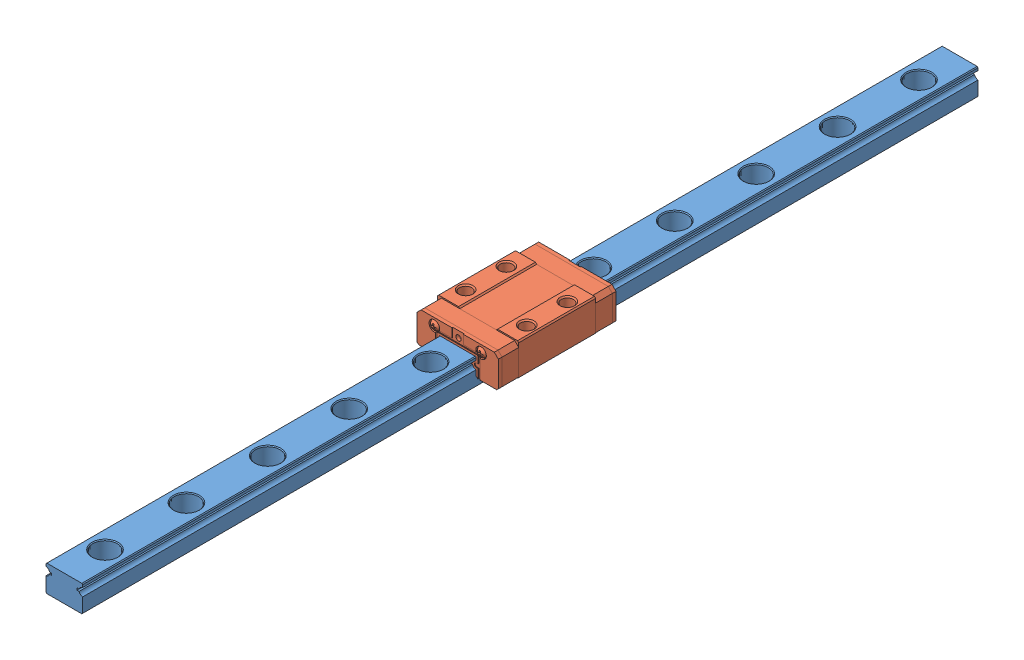
SolidWorks assembly MGN9C-250, configuration По умолчанию. Lengths in mm.
Overall size (20 10 220).
2 component instances, 2 part files, 3 mates.
Components (placement in the parent):
- MGNR9-1: MGNR9 [По умолчанию] at origin size (9 6.5 220)
- MGN9C-1: MGN9C [По умолчанию] at (0 2.75 108.8941) size (20 8 29.67)
Mates (geometry in assembly coordinates):
- 重合/共線/共點1: coordinate: point of MGNR9-1
- 同軸心1: concentric anti-aligned: cylinder of MGNR9-1 through (-4.6 1.45 220) axis (0 0 -1) radius 1; cylinder of MGN9C-1 through (-4.6 1.45 94.4441) axis (0 0 1) radius 1
- 同軸心2: concentric anti-aligned: cylinder of MGNR9-1 through (4.6 1.45 220) axis (0 0 -1) radius 1; cylinder of MGN9C-1 through (4.6 1.45 94.4441) axis (0 0 1) radius 1
